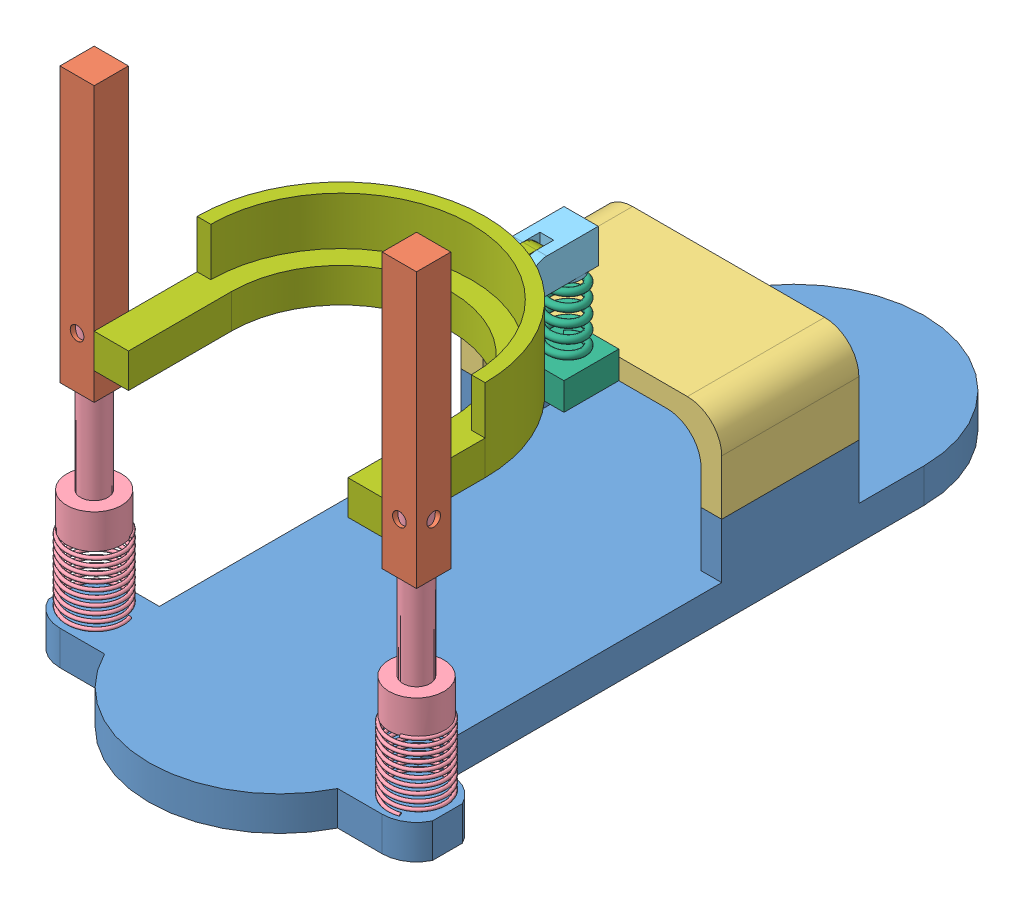
SolidWorks assembly shoes_v0.3, configuration 默认. Lengths in mm.
Overall size (148.8 147 226).
9 component instances, 7 part files, 23 mates.
Components (placement in the parent):
- shoes_base_v0.3-1: shoes_base_v0.3 [Default] at (-2.4297 -36.7628 226) size (148.8 26 226)
- shoes_pole_a_v0.3-1: shoes_pole_a_v0.3 [默认] at (44.5703 110.2372 308) x (0 0 -1) z (-1 0 0) size (10 80 10)
- shoes_pole_a_v0.3-2: shoes_pole_a_v0.3 [默认] at (-49.4297 110.2372 308) x (0 0 -1) z (-1 0 0) size (10 80 10)
- shoes_top_v0.3-1: shoes_top_v0.3 [Default] at (-2.4297 -24.7628 170) size (76 26 40)
- shoes_pole_b_v0.3-1: shoes_pole_b_v0.3 [默认] at (-49.4297 83.2372 308) x (-0.908693 0 -0.417465) z (-0.417465 0 0.908693) size (17.69 111 17.67)
- shoes_pole_b_v0.3-2: shoes_pole_b_v0.3 [默认] at (44.5703 83.2372 308) x (0.413739 0 -0.910396) z (-0.910396 0 -0.413739) size (17.69 111 17.67)
- pole_p1_v0.3-1: pole_p1_v0.3 [默认] at (-2.4297 38.2372 218) x (0 0 -1) z (1 0 0) size (20 11 10)
- tri_rotate_unit_v0.3-1: tri_rotate_unit_v0.3 [默认] at (-2.4297 9.2372 218) size (16 29.98 16)
- vervel_v0.3-1: vervel_v0.3 [默认] at (-2.4297 38.2372 283) size (84 24 90)
Mates (geometry in assembly coordinates):
- 重合29: coincident anti-aligned: plane of shoes_v0.4-1 through (-2.4297 -10.7628 226) normal (0 1 0); plane of shoes_top-1 through (35.5703 -10.7628 210) normal (0 -1 0)
- 重合30: coincident aligned: plane of shoes_v0.4-1 through (35.5703 -10.7628 210) normal (0 0 1); plane of shoes_top-1 through (-24.0458 -0.7628 210) normal (0 0 1)
- 重合31: coincident aligned: line of shoes_v0.4-1 through (35.5703 -10.7628 210) axis (0 0 -1); line of shoes_top-1 through (35.5703 -10.7628 210) axis (0 0 -1)
- 同心25: concentric anti-aligned: cylinder of shoes_pole_a_v0.2-2 through (-49.4297 105.2372 308) axis (0 -1 0) radius 4; cylinder of shoes_pole_b_v0.3-1 through (-49.4297 3.2372 308) axis (0 1 0) radius 4
- 同心26: concentric anti-aligned: cylinder of shoes_pole_a_v0.2-1 through (44.5703 105.2372 308) axis (0 -1 0) radius 4; cylinder of shoes_pole_b_v0.3-2 through (44.5703 3.2372 308) axis (0 1 0) radius 4
- 同心30: concentric aligned: cylinder of pole_p1_v0.3-1 through (-2.4297 37.2372 218) axis (0 1 0) radius 5; circle of tri_rotate_unit_v0.3-1
- 重合35: coincident anti-aligned: plane of pole_p1_v0.3-1 through (-2.4297 37.2372 218) normal (0 -1 0); plane of tri_rotate_unit_v0.3-1 through (-2.4297 37.2372 218) normal (0 1 0)
- 平行1: parallel aligned: plane of shoes_top_v0.2-1 through (-24.0458 -0.7628 170) normal (0 0 -1); plane of tri_rotate_unit_v0.3-1 through (-10.4297 17.2372 210) normal (0 0 -1)
- 重合36: coincident aligned: plane of shoes_top_v0.2-1 through (19.5703 9.2372 210) normal (0 -1 0); plane of tri_rotate_unit_v0.3-1 through (-2.4297 9.2372 218) normal (0 -1 0)
- 平行2: parallel aligned: plane of shoes_top_v0.2-1 through (-24.0458 -0.7628 170) normal (0 0 -1); plane of pole_p1_v0.3-1 through (-7.4297 48.2372 213) normal (0 0 -1)
- 距离1: distance = 30 mm aligned: plane of tri_rotate_unit_v0.3-1 through (5.5703 17.2372 210) normal (1 0 0); plane of shoes_top_v0.2-1 through (35.5703 -4.7628 210) normal (1 0 0)
- 同心31: concentric anti-aligned: cylinder of pole_p1_v0.3-1 through (-7.4297 43.2372 228) axis (1 0 0) radius 5; cylinder of vervel_v0.3-1 through (5.5703 43.2372 228) axis (-1 0 0) radius 5
- 重合41: coincident anti-aligned: plane of pole_p1_v0.3-1 through (-4.4297 48.2372 233) normal (1 0 0); plane of vervel_v0.3-1 through (-4.4297 48.2372 247) normal (-1 0 0)
- 重合42: coincident aligned: plane of pole_p1_v0.3-1 through (-2.4297 48.2372 218) normal (0 1 0); plane of vervel_v0.3-1 through (-2.4297 48.2372 283) normal (0 1 0)
- 重合50: coincident anti-aligned: plane of shoes_base_v0.2-1 through (-2.4297 -26.7628 301) normal (0 1 0); plane of shoes_pole_b_v0.3-1 through (-49.4297 -26.7628 308) normal (0 -1 0)
- 重合51: coincident anti-aligned: plane of shoes_base_v0.2-1 through (-2.4297 -26.7628 301) normal (0 1 0); plane of shoes_pole_b_v0.3-2 through (44.5703 -26.7628 308) normal (0 -1 0)
- 重合53: coincident anti-aligned: plane of shoes_top_v0.2-1 through (-24.0458 -0.7628 210) normal (0 0 1); plane of tri_rotate_unit_v0.3-1 through (-10.4297 17.2372 210) normal (0 0 -1)
- 距离5: distance = 8 mm aligned: plane of shoes_pole_a_v0.2-1 through (44.5703 30.2372 308) normal (0 -1 0); plane of vervel_v0.3-1 through (-2.4297 38.2372 283) normal (0 -1 0)
- 重合54: coincident anti-aligned: plane of shoes_pole_a_v0.2-1 through (39.5703 30.2372 313) normal (-1 0 0); plane of vervel_v0.3-1 through (39.5703 48.2372 283) normal (1 0 0)
- 重合55: coincident aligned: plane of shoes_pole_a_v0.2-1 through (49.5703 30.2372 313) normal (0 0 1); plane of vervel_v0.3-1 through (-2.4297 48.2372 313) normal (0 0 1)
- 重合56: coincident anti-aligned: plane of shoes_pole_a_v0.2-2 through (-44.4297 30.2372 313) normal (1 0 0); plane of vervel_v0.3-1 through (-44.4297 48.2372 283) normal (-1 0 0)
- 重合57: coincident aligned: plane of shoes_pole_a_v0.2-2 through (-44.4297 30.2372 313) normal (0 0 1); plane of vervel_v0.3-1 through (-2.4297 48.2372 313) normal (0 0 1)
- 距离6: distance = 8 mm aligned: plane of shoes_pole_a_v0.2-2 through (-49.4297 30.2372 308) normal (0 -1 0); plane of vervel_v0.3-1 through (-2.4297 38.2372 283) normal (0 -1 0)
